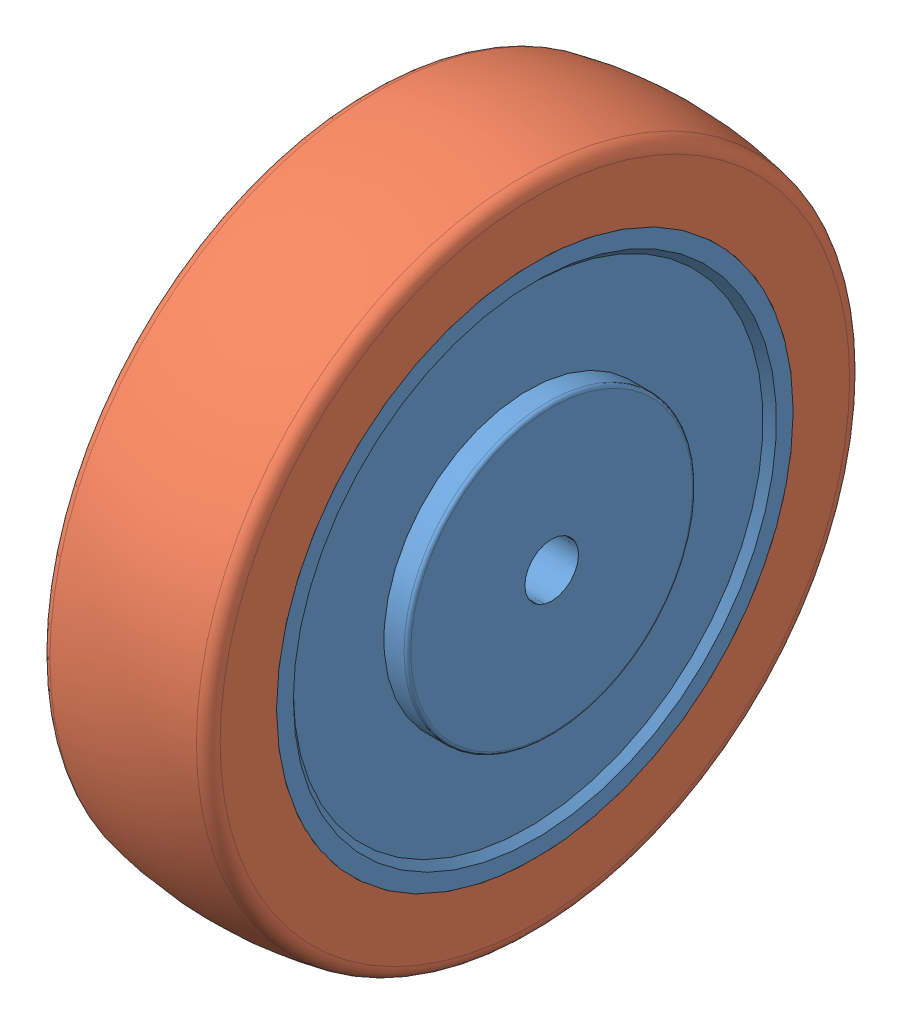
SolidWorks assembly wheel, configuration ﾃﾞﾌｫﾙﾄ. Lengths in mm.
Overall size (30 100 100).
2 component instances, 2 part files, 2 mates.
Components (placement in the parent):
- wheel_plate-1: wheel_plate [ﾃﾞﾌｫﾙﾄ] at (-16.9454 0.9806 100) x (0 -1 0) z (0 0 1) size (77 30 77)
- caster_tire-1: caster_tire [ﾃﾞﾌｫﾙﾄ] at (-4.4454 0.9806 100) size (25 100 100)
Mates (geometry in assembly coordinates):
- 同心円1: concentric: cylinder of wheel_plate-1 through (8.0546 0.9806 100) axis (-1 0 0) radius 38.5; cylinder of caster_tire-1 through (-16.9454 0.9806 100) axis (1 0 0) radius 38.5
- 一致2: coincident aligned: plane of wheel_plate-1 through (-16.9454 0.9806 100) normal (-1 0 0); plane of caster_tire-1 through (-16.9454 0.9806 100) normal (-1 0 0)
